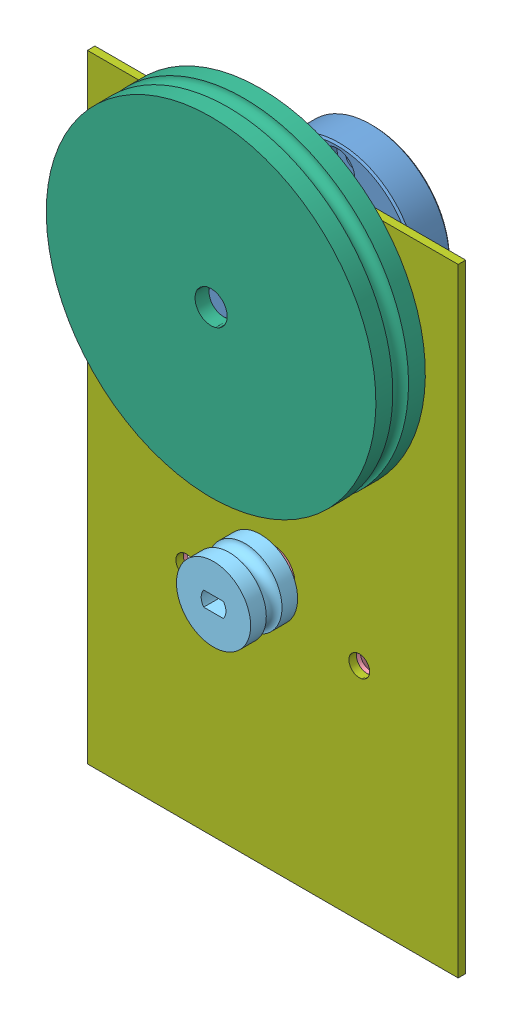
SolidWorks assembly astro-mount, configuration Default. Lengths in mm.
Overall size (75 138.34 33).
7 component instances, 7 part files, 17 mates.
Components (placement in the parent):
- 2435K120_IDLER SHAFT-1: 2435K120_IDLER SHAFT [2435K12] at origin size (31.75 31.75 30.61)
- 2848N100_FLANGE-MNT BRNG HOUSING-1: 2848N100_FLANGE-MNT BRNG HOUSING [2848N1] at (0 0 3.5814) x (-1 0 0) z (0 0 -1) size (41.27 19.05 9.53)
- 6389K625_LIGHT DTY DRY-RUNNING SLEEVE BRNG-1: 6389K625_LIGHT DTY DRY-RUNNING SLEEVE BRNG [6389K625] at (0 0 -7.5311) x (-0.998859 -0.04775 0) z (-0.04775 0.998859 0) size (15.88 9.53 15.88)
- stepper motor-1: stepper motor [Default] at (0 -60.2991 3.5814) x (1 0 0) z (0 -1 0) size (42 29 31)
- drive pulley-1: drive pulley [Default] at (0 -52.2991 17.0814) x (1 0 0) z (0 1 0) size (15 9.5 15)
- follower pulley-1: follower pulley [Default] at (0 0 7.5814) x (1 0 0) z (0 -1 0) size (66.67 10 66.67)
- mounting plate-1: mounting plate [Default] at (0 0 3.5814) size (75 125 1.52)
Mates (geometry in assembly coordinates):
- Concentric1: concentric anti-aligned: cylinder of 2848N100_FLANGE-MNT BRNG HOUSING-1 through (0 0 -1.1811) axis (0 0 1) radius 6.35; cylinder of 6389K625_LIGHT DTY DRY-RUNNING SLEEVE BRNG-1 through (0 0 1.9939) axis (0 0 -1) radius 6.35
- Concentric2: concentric aligned: cylinder of 2435K120_IDLER SHAFT-1 through (0 0 -15.0812) axis (0 0 -1) radius 4.7625; cylinder of 6389K625_LIGHT DTY DRY-RUNNING SLEEVE BRNG-1 through (0 0 1.9939) axis (0 0 -1) radius 4.8006
- Coincident1: coincident anti-aligned: plane of 2848N100_FLANGE-MNT BRNG HOUSING-1 through (0 0 -5.9436) normal (0 0 -1); plane of 6389K625_LIGHT DTY DRY-RUNNING SLEEVE BRNG-1 through (0 0 -5.9436) normal (0 0 1)
- Coincident2: coincident anti-aligned: plane of 2435K120_IDLER SHAFT-1 through (0 4.7625 -7.5311) normal (0 0 1); plane of 6389K625_LIGHT DTY DRY-RUNNING SLEEVE BRNG-1 through (0 0 -7.5311) normal (0 0 -1)
- Coincident3: coincident aligned: plane of 2848N100_FLANGE-MNT BRNG HOUSING-1; plane of assembly through (0 0 0) normal (0 1 0)
- Coincident4: coordinate: point of 2435K120_IDLER SHAFT-1; point of assembly
- Coincident5: coincident aligned: plane of 2848N100_FLANGE-MNT BRNG HOUSING-1 through (15.875 0 3.5814) normal (0 0 1); plane of stepper motor-1 through (0 -60.2991 3.5814) normal (0 0 1)
- Coincident6: coincident aligned: plane of stepper motor-1; plane of assembly through (0 0 0) normal (1 0 0)
- Coincident7: coincident anti-aligned: plane of stepper motor-1 through (0 -53.7991 7.5814) normal (0 -1 0); plane of drive pulley-1 through (-2 -53.7991 7.5814) normal (0 1 0)
- Concentric3: concentric anti-aligned: cylinder of stepper motor-1 through (0 -52.2991 13.5814) axis (0 0 -1) radius 2.5; cylinder of drive pulley-1 through (0 -52.2991 7.5814) axis (0 0 1) radius 2.5
- Coincident8: coincident anti-aligned: plane of stepper motor-1 through (0 -60.2991 7.5814) normal (0 0 1); plane of drive pulley-1 through (0 -52.2991 7.5814) normal (0 0 -1)
- Concentric4: concentric anti-aligned: cylinder of 2435K120_IDLER SHAFT-1 through (0 0 -15.0812) axis (0 0 -1) radius 4.7625; cylinder of follower pulley-1 through (0 0 17.5814) axis (0 0 1) radius 3.2639
- Coincident9: coincident aligned: plane of drive pulley-1 through (0 -52.2991 7.5814) normal (0 0 -1); plane of follower pulley-1 through (0 0 7.5814) normal (0 0 -1)
- InPlace1: in place: plane of 2848N100_FLANGE-MNT BRNG HOUSING-1 through (15.875 0 3.5814) normal (0 0 1); plane of mounting plate-1 through (0 0 3.5814) normal (0 0 1); moOrthogonalPlaneRef_w of 2848N100_FLANGE-MNT BRNG HOUSING-1 through (15.875 0 3.5814) normal (0 0 1); plane of mounting plate-1 through (0 0 3.5814) normal (0 1 0); plane of 2848N100_FLANGE-MNT BRNG HOUSING-1 through (15.875 0 3.5814) normal (0 0 1); plane of mounting plate-1 through (0 0 3.5814) normal (1 0 0); plane of 2848N100_FLANGE-MNT BRNG HOUSING-1 through (15.875 0 3.5814) normal (0 0 1); unknown of mounting plate-1
- Coincident10: coincident aligned: plane of 2848N100_FLANGE-MNT BRNG HOUSING-1; plane of mounting plate-1
- Coincident11: coincident aligned: moOrthogonalPlaneRef_w of 2848N100_FLANGE-MNT BRNG HOUSING-1 through (0 0 3.5814) normal (0 1 0); plane of mounting plate-1 through (0 0 3.5814) normal (0 1 0)
- Coincident12: coincident anti-aligned: moOrthogonalPlaneRef_w of 2848N100_FLANGE-MNT BRNG HOUSING-1 through (0 0 3.5814) normal (-1 0 0); plane of mounting plate-1 through (0 0 3.5814) normal (1 0 0)
